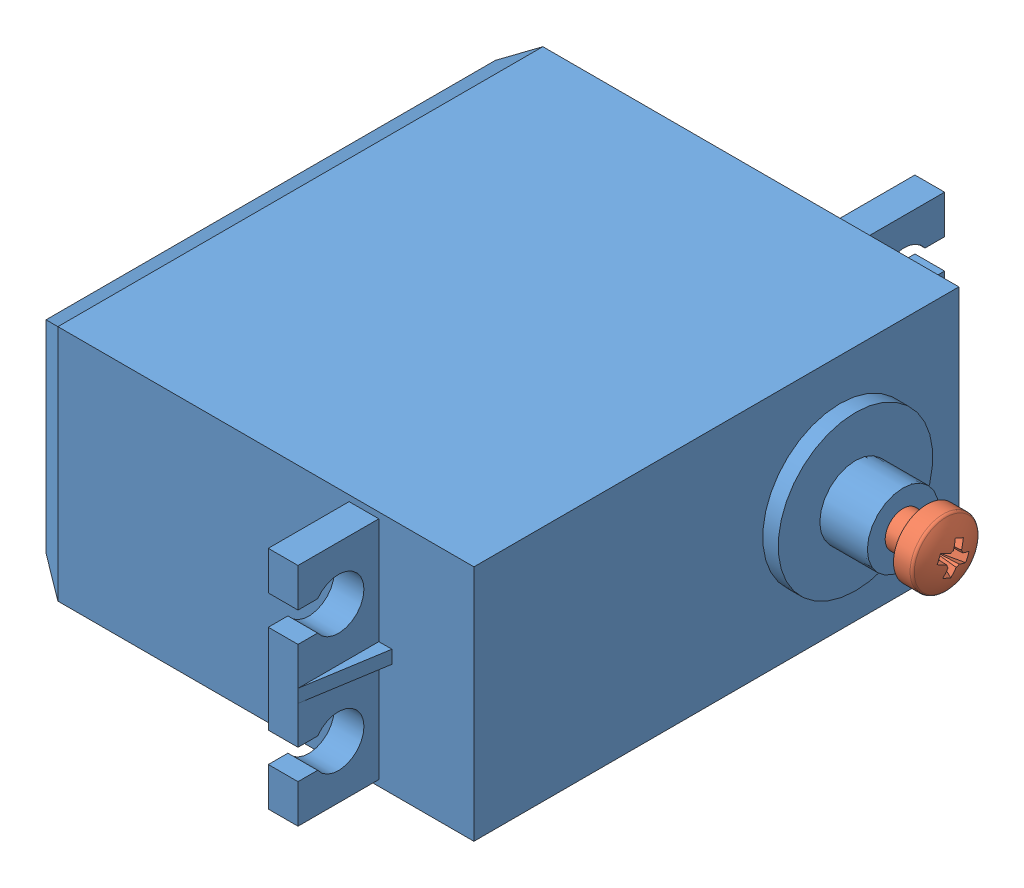
SolidWorks assembly PARALLAX servo assy, configuration Standard. Lengths in mm.
Overall size (47.15 20 54.4).
2 component instances, 2 part files, 2 mates.
Components (placement in the parent):
- Servo body housing-1: Servo body housing [Standard] at origin size (42.8 20 54.4)
- pan head cross recess screw_din-2: pan head cross recess screw_din [ISO 7045 - M3 x 8 - Z --- 8N] at (28.45 0 10) x (-1 0 0) z (0 -0.401567 -0.91583) size (10.35 5.6 5.6)
Mates (geometry in assembly coordinates):
- Concentric1: concentric aligned: cylinder of Servo body housing-1 through (24.05 0 10) axis (1 0 0) radius 1.25; cylinder of pan head cross recess screw_din-2 through (53.85 0 10) axis (1 0 0) radius 1.5
- Distance1: distance = 2 mm anti-aligned: plane of Servo body housing-1 through (24.05 0 10) normal (1 0 0); plane of pan head cross recess screw_din-2 through (26.05 1.3737 9.3976) normal (-1 0 0)
